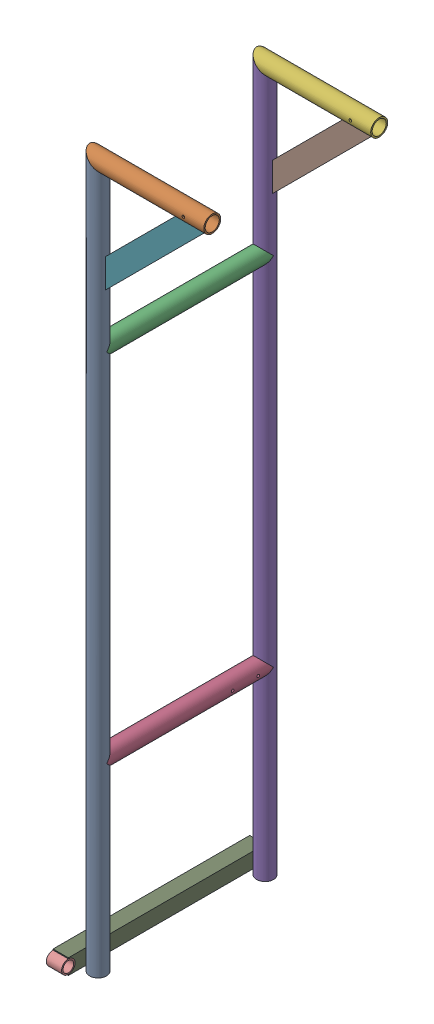
SolidWorks assembly GE-16046_ASM, configuration Default. Lengths in mm.
Overall size (342.9 1771.65 505.65).
10 component instances, 7 part files, 0 mates.
Components (placement in the parent):
- GE-16046-01-1: GE-16046-01 [Default] at origin size (42.16 1771.65 42.16)
- GE-16046-02-1: GE-16046-02 [Default] at (131.318 864.743 0) x (0 -1 0) z (0 0 -1) size (42.16 304.8 42.16)
- GE-16046-03-1: GE-16046-03 [Default] at (0 457.2 -207.518) x (0 1 0) z (1 0 0) size (42.16 415.04 42.16)
- GE-16046-04-1: GE-16046-04 [Default] at (0 -428.625 -207.518) x (0 1 0) z (1 0 0) size (42.16 415.04 42.16)
- GE-16046-01-2: GE-16046-01 [Default] at (0 0 -415.036) size (42.16 1771.65 42.16)
- GE-16046-02-2: GE-16046-02 [Default] at (131.318 864.743 -415.036) x (0 -1 0) z (0 0 -1) size (42.16 304.8 42.16)
- GE-16046-05-1: GE-16046-05 [Default] at (146.8056 753.8584 0) x (0.707107 0.707107 0) z (0 0 1) size (355.6 50.8 6.35)
- GE-16046-05-2: GE-16046-05 [Default] at (146.8056 753.8584 -415.036) x (0.707107 0.707107 0) z (0 0 1) size (355.6 50.8 6.35)
- GE-16046-06-1: GE-16046-06 [Default] at (-40.132 -860.425 -191.643) x (-1 0 0) z (0 0 -1) size (38.1 38.1 488.95)
- GE-16046-07-1: GE-16046-07 [Default] at (-40.132 -860.425 52.832) x (0 -1 0) z (0 0 1) size (33.4 38.1 33.4)
